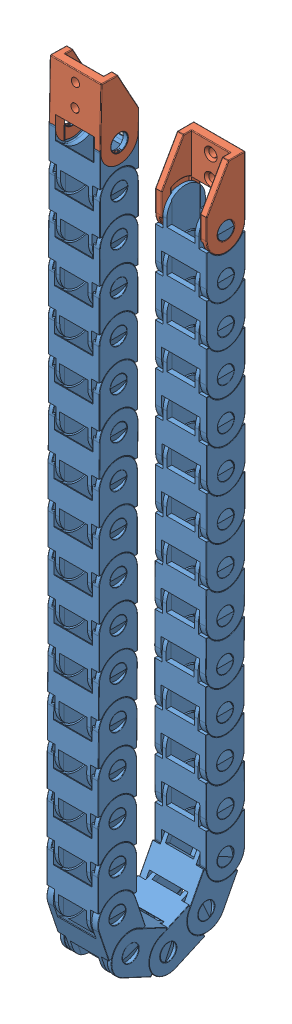
SolidWorks assembly esteira assy eixo y, configuration Valor predeterminado. Lengths in mm.
Overall size (18.81 294.87 57.67).
35 component instances, 2 part files, 0 mates.
Components (placement in the parent):
- esteira 15mm meio-1: esteira 15mm meio [Valor predeterminado] at (-22.3167 -385.4947 64.2503) x (-1 0 0) z (0 0.317305 -0.948324) size (18.71 29.17 14)
- esteira 15mm ponta-1: esteira 15mm ponta [Valor predeterminado] at (-22.318 -173.1904 13.4249) x (-1 0 0) z (0 0 1) size (18.71 28.52 14)
- esteira 15mm meio-2: esteira 15mm meio [Valor predeterminado] at (-22.3387 -388.0033 37.6001) x (1 0 0) z (0 -0.913545 -0.406737) size (18.71 29.17 14)
- esteira 15mm meio-3: esteira 15mm meio [Valor predeterminado] at (-22.3146 -249.0126 27.4078) x (1 0 0) z (0 0 -1) size (18.71 29.17 14)
- esteira 15mm meio-4: esteira 15mm meio [Valor predeterminado] at (-22.3271 -324.9133 27.7164) x (1 0 0) z (0 0 -1) size (18.71 29.17 14)
- esteira 15mm meio-5: esteira 15mm meio [Valor predeterminado] at (-22.3222 -381.4774 30.4113) x (1 0 0) z (0 -0.461749 -0.887011) size (18.71 29.17 14)
- esteira 15mm meio-6: esteira 15mm meio [Valor predeterminado] at (-22.334 -355.3333 27.6189) x (1 0 0) z (0 0.008727 -0.999962) size (18.71 29.17 14)
- esteira 15mm meio-7: esteira 15mm meio [Valor predeterminado] at (-22.3341 -387.6186 45.5345) x (1 0 0) z (0 -0.906308 0.422618) size (18.71 29.17 14)
- esteira 15mm meio-8: esteira 15mm meio [Valor predeterminado] at (-22.3247 -322.9926 52.7684) x (1 0 0) z (0 0.008727 0.999962) size (18.71 29.17 14)
- esteira 15mm meio-9: esteira 15mm meio [Valor predeterminado] at (-22.3384 -307.7895 52.6373) x (1 0 0) z (0 0.008727 0.999962) size (18.71 29.17 14)
- esteira 15mm meio-11: esteira 15mm meio [Valor predeterminado] at (-22.3209 -262.1913 52.5803) size (18.71 29.17 14)
- esteira 15mm meio-12: esteira 15mm meio [Valor predeterminado] at (-22.3466 -231.8827 52.4074) x (1 0 0) z (0 0.008727 0.999962) size (18.71 29.17 14)
- esteira 15mm meio-13: esteira 15mm meio [Valor predeterminado] at (-22.3232 -368.5059 52.8569) size (18.71 29.17 14)
- esteira 15mm meio-14: esteira 15mm meio [Valor predeterminado] at (-22.324 -277.3762 52.553) size (18.71 29.17 14)
- esteira 15mm meio-15: esteira 15mm meio [Valor predeterminado] at (-22.3388 -201.4377 52.4327) size (18.71 29.17 14)
- esteira 15mm meio-16: esteira 15mm meio [Valor predeterminado] at (-22.3225 -353.3076 52.8596) size (18.71 29.17 14)
- esteira 15mm meio-17: esteira 15mm meio [Valor predeterminado] at (-22.3279 -247.0151 52.5574) size (18.71 29.17 14)
- esteira 15mm meio-18: esteira 15mm meio [Valor predeterminado] at (-22.3256 -292.5631 52.5622) size (18.71 29.17 14)
- esteira 15mm meio-19: esteira 15mm meio [Valor predeterminado] at (-22.3305 -216.6139 52.4266) size (18.71 29.17 14)
- esteira 15mm meio-20: esteira 15mm meio [Valor predeterminado] at (-22.3221 -171.0879 52.3443) x (1 0 0) z (0 0.008727 0.999962) size (18.71 29.17 14)
- esteira 15mm meio-21: esteira 15mm meio [Valor predeterminado] at (-22.3231 -186.249 52.4208) size (18.71 29.17 14)
- esteira 15mm meio-22: esteira 15mm meio [Valor predeterminado] at (-22.322 -338.1238 52.8394) size (18.71 29.17 14)
- esteira 15mm meio-25: esteira 15mm meio [Valor predeterminado] at (-22.3119 -340.0523 27.7115) x (1 0 0) z (0 0 -1) size (18.71 29.17 14)
- esteira 15mm meio-27: esteira 15mm meio [Valor predeterminado] at (-22.3231 -140.6384 52.1621) size (18.71 29.17 14)
- esteira 15mm meio-29: esteira 15mm meio [Valor predeterminado] at (-22.3273 -155.8576 52.2339) size (18.71 29.17 14)
- esteira 15mm meio-30: esteira 15mm meio [Valor predeterminado] at (-22.3109 -309.6566 27.6571) x (1 0 0) z (0 -0.008727 -0.999962) size (18.71 29.17 14)
- esteira 15mm meio-31: esteira 15mm meio [Valor predeterminado] at (-22.3151 -370.4492 27.5827) x (1 0 0) z (0 0 -1) size (18.71 29.17 14)
- esteira 15mm meio-32: esteira 15mm meio [Valor predeterminado] at (-22.4083 -279.3752 27.4303) x (1 0 0) z (0 0 -1) size (18.71 29.17 14)
- esteira 15mm meio-33: esteira 15mm meio [Valor predeterminado] at (-22.3793 -218.647 27.418) x (1 0 0) z (0 0 -1) size (18.71 29.17 14)
- esteira 15mm meio-35: esteira 15mm meio [Valor predeterminado] at (-22.3359 -233.829 27.4223) x (1 0 0) z (0 0 -1) size (18.71 29.17 14)
- esteira 15mm meio-36: esteira 15mm meio [Valor predeterminado] at (-22.3849 -294.5033 27.5145) x (1 0 0) z (0 -0.008727 -0.999962) size (18.71 29.17 14)
- esteira 15mm meio-37: esteira 15mm meio [Valor predeterminado] at (-22.3863 -264.2052 27.4154) x (1 0 0) z (0 0 -1) size (18.71 29.17 14)
- esteira 15mm meio-39: esteira 15mm meio [Valor predeterminado] at (-22.318 -188.3174 27.4462) x (1 0 0) z (0 0 -1) size (18.71 29.17 14)
- esteira 15mm meio-40: esteira 15mm meio [Valor predeterminado] at (-22.3238 -203.4893 27.433) x (1 0 0) z (0 0 -1) size (18.71 29.17 14)
- esteira 15mm ponta-2: esteira 15mm ponta [Valor predeterminado] at (-22.3155 -125.9961 66.0136) x (1 0 0) z (0 -0.017452 -0.999848) size (18.71 28.52 14)
